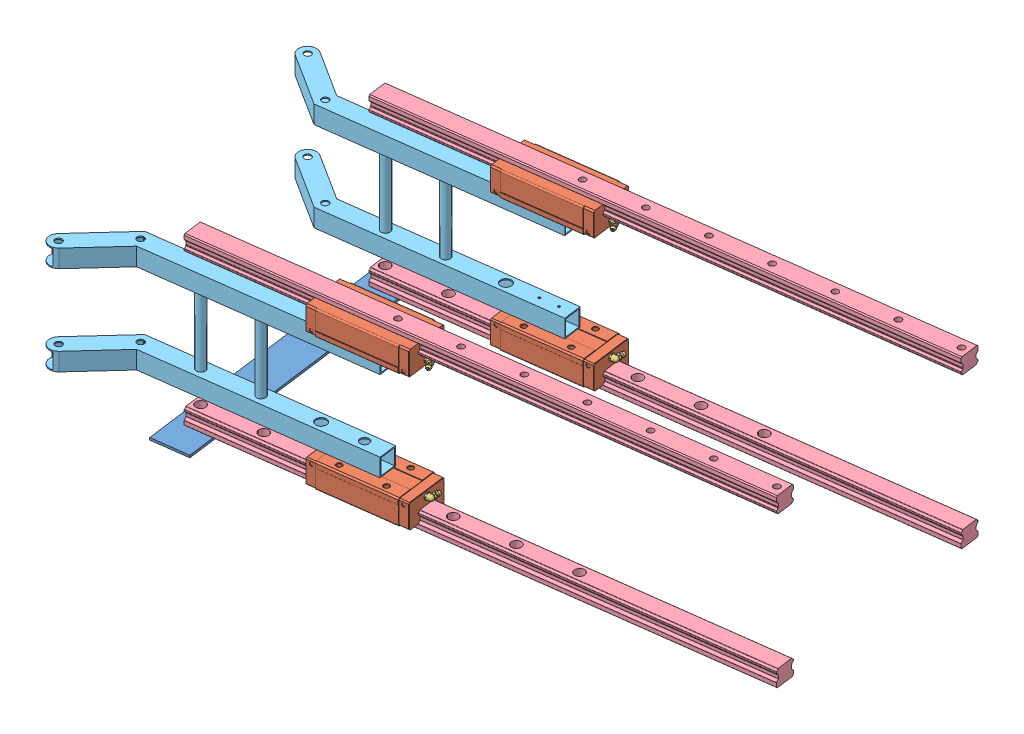
SolidWorks assembly armLayout, configuration Default. Lengths in mm.
Overall size (934.33 239.58 497.67).
19 component instances, 5 part files, 28 mates.
Components (placement in the parent):
- bottomSpacer-1: bottomSpacer [Default] at (-15.1295 99.3371 437.2342) x (-0.130526 0 -0.991445) z (0.991445 0 -0.130526) size (406.4 3.17 50.8)
- SHS30LV1SS Carriage-1: SHS30LV1SS Carriage [Default] at (446.9633 102.5121 222.6835) x (-0.991445 0 0.130526) z (-0.130526 0 -0.991445) size (142.6 35 60)
  - SHS30LVSSB-M6F1 Slide25-55-1: SHS30LVSSB-M6F1 Slide25-55 [Default] at (265.2705 7 0) size (131 35 60)
  - B-M6F-SHS_grease_nipple_joint-1: B-M6F-SHS_grease_nipple_joint [Default] at (199.7705 34 0) x (1 0 0) z (0 0.256332 0.966589) size (16.6 9.24 15.31)
- SHS30LV50010 Track-1: SHS30LV50010 Track [Default] at (728.5174 338.9121 493.0463) x (-0.991445 0 0.130526) z (0.130526 0 0.991445) size (750 23 28)
- SHS30LV1SS Carriage-2: SHS30LV1SS Carriage [Default] at (486.7476 338.9121 524.8759) x (-0.991445 0 0.130526) z (0.130526 0 0.991445) size (142.6 35 60)
  - SHS30LVSSB-M6F1 Slide25-55-1: SHS30LVSSB-M6F1 Slide25-55 [Default] at (265.2705 7 0) size (131 35 60)
  - B-M6F-SHS_grease_nipple_joint-1: B-M6F-SHS_grease_nipple_joint [Default] at (199.7705 34 0) x (1 0 0) z (0 0.256332 0.966589) size (16.6 9.24 15.31)
- SHS30LV1SS Carriage-3: SHS30LV1SS Carriage [Default] at (486.7476 102.5121 524.8759) x (-0.991445 0 0.130526) z (-0.130526 0 -0.991445) size (142.6 35 60)
  - SHS30LVSSB-M6F1 Slide25-55-1: SHS30LVSSB-M6F1 Slide25-55 [Default] at (265.2705 7 0) size (131 35 60)
  - B-M6F-SHS_grease_nipple_joint-1: B-M6F-SHS_grease_nipple_joint [Default] at (199.7705 34 0) x (1 0 0) z (0 0.256332 0.966589) size (16.6 9.24 15.31)
- SHS30LV1SS Carriage-4: SHS30LV1SS Carriage [Default] at (446.9633 338.9121 222.6835) x (-0.991445 0 0.130526) z (0.130526 0 0.991445) size (142.6 35 60)
  - SHS30LVSSB-M6F1 Slide25-55-1: SHS30LVSSB-M6F1 Slide25-55 [Default] at (265.2705 7 0) size (131 35 60)
  - B-M6F-SHS_grease_nipple_joint-1: B-M6F-SHS_grease_nipple_joint [Default] at (199.7705 34 0) x (1 0 0) z (0 0.256332 0.966589) size (16.6 9.24 15.31)
- SHS30LV50010 Track-2: SHS30LV50010 Track [Default] at (4.7627 102.5121 588.3304) x (0.991445 0 -0.130526) z (0.130526 0 0.991445) size (750 23 28)
- SHS30LV50010 Track-3: SHS30LV50010 Track [Default] at (-35.0217 102.5121 286.138) x (0.991445 0 -0.130526) z (0.130526 0 0.991445) size (750 23 28)
- SHS30LV50010 Track-4: SHS30LV50010 Track [Default] at (688.7331 338.9121 190.8539) x (-0.991445 0 0.130526) z (0.130526 0 0.991445) size (750 23 28)
- intakeArm-1: intakeArm [Default] at (-110.1995 296.9121 296.0354) x (-0.991445 0 0.130526) z (0.130526 0 0.991445) size (388.86 152.4 78.46)
- intakeArm-2: intakeArm [Default] at (-70.4151 144.5121 598.2278) x (-0.991445 0 0.130526) z (-0.130526 0 -0.991445) size (388.86 152.4 78.46)
Mates (geometry in assembly coordinates):
- Coincident11: coincident anti-aligned: plane of SHS30LV50010 Track-1 through (-6.6067 315.9121 578.5841) normal (0 -1 0); plane of SHS30LV1SS Carriage-2/SHS30LVSSB-M6F1 Slide25-55-1 through (157.352 315.9121 556.9985) normal (0 1 0)
- Coincident12: coincident: plane of SHS30LV50010 Track-1 through (-6.9791 320.5605 575.7554) normal (-0.130526 0 -0.991445); plane of SHS30LV1SS Carriage-2/SHS30LVSSB-M6F1 Slide25-55-1 through (156.9796 320.5605 554.1699) normal (0.130526 0 0.991445)
- Coincident13: coincident: plane of SHS30LV1SS Carriage-3/SHS30LVSSB-M6F1 Slide25-55-1 through (160.2619 125.5121 579.1017) normal (0 -1 0); plane of SHS30LV50010 Track-2 through (736.9769 125.5121 480.6894) normal (0 1 0)
- Coincident14: coincident: plane of SHS30LV1SS Carriage-3/SHS30LVSSB-M6F1 Slide25-55-1 through (160.6343 120.8637 581.9303) normal (-0.130526 0 -0.991445); plane of SHS30LV50010 Track-2 through (740.2593 122.6605 505.6213) normal (0.130526 0 0.991445)
- Coincident15: coincident: plane of SHS30LV50010 Track-1 through (740.2652 315.8616 505.6666) normal (0.991445 0 -0.130526); plane of SHS30LV50010 Track-2 through (740.2652 125.5626 505.6666) normal (0.991445 0 -0.130526)
- Coincident16: coincident anti-aligned: plane of SHS30LV1SS Carriage-1/SHS30LVSSB-M6F1 Slide25-55-1 through (120.4775 125.5121 276.9093) normal (0 -1 0); plane of SHS30LV50010 Track-3 through (697.1925 125.5121 178.497) normal (0 1 0)
- Coincident17: coincident: plane of SHS30LV1SS Carriage-1/SHS30LVSSB-M6F1 Slide25-55-1 through (117.1952 122.6605 251.9775) normal (0.130526 0 0.991445); plane of SHS30LV50010 Track-3 through (696.8201 120.8637 175.6684) normal (-0.130526 0 -0.991445)
- Coincident18: coincident: plane of SHS30LV1SS Carriage-4/SHS30LVSSB-M6F1 Slide25-55-1 through (117.5676 315.9121 254.8061) normal (0 1 0); plane of SHS30LV50010 Track-4 through (-46.3911 315.9121 276.3917) normal (0 -1 0)
- Coincident19: coincident: plane of SHS30LV1SS Carriage-4/SHS30LVSSB-M6F1 Slide25-55-1 through (117.1952 320.5605 251.9775) normal (0.130526 0 0.991445); plane of SHS30LV50010 Track-4 through (-46.7635 320.5605 273.5631) normal (-0.130526 0 -0.991445)
- Coincident20: coincident: plane of SHS30LV50010 Track-3 through (700.4808 125.5626 203.4742) normal (0.991445 0 -0.130526); plane of SHS30LV50010 Track-4 through (700.4808 315.8616 203.4742) normal (0.991445 0 -0.130526)
- Concentric16: concentric: circle of bottomSpacer-1; circle of SHS30LV50010 Track-3
- Coincident21: coincident: plane of bottomSpacer-1 through (-15.1295 102.5121 437.2342) normal (0 1 0); plane of SHS30LV50010 Track-3 through (700.2791 102.5121 201.9417) normal (0 -1 0)
- Concentric17: concentric: cylinder of bottomSpacer-1 through (4.7627 102.5121 588.3304) axis (0 -1 0) radius 6.35; circle of SHS30LV50010 Track-2
- Coincident22: coincident: plane of bottomSpacer-1 through (-15.1295 102.5121 437.2342) normal (0 1 0); plane of SHS30LV50010 Track-2 through (740.0635 102.5121 504.1341) normal (0 -1 0)
- Coincident31: coincident: plane of SHS30LV1SS Carriage-1/SHS30LVSSB-M6F1 Slide25-55-1 through (120.4775 125.5121 276.9093) normal (0 -1 0); plane of SHS30LV50010 Track-3 through (697.1925 125.5121 178.497) normal (0 1 0)
- Concentric18: concentric: cylinder of SHS30LV1SS Carriage-3/SHS30LVSSB-M6F1 Slide25-55-1 through (191.3927 132.9933 543.5875) axis (0 1 0) radius 3.3235; cylinder of intakeArm-2 through (31.8314 135.1076 564.5942) axis (0 1 0) radius 3.325
- Concentric19: concentric: circle of SHS30LV1SS Carriage-3/SHS30LVSSB-M6F1 Slide25-55-1; circle of intakeArm-2
- Coincident32: coincident anti-aligned: plane of SHS30LV1SS Carriage-3/SHS30LVSSB-M6F1 Slide25-55-1 through (175.3505 144.5121 594.1137) normal (0 1 0); plane of intakeArm-2 through (-70.4151 144.5121 598.2278) normal (0 -1 0)
- Concentric20: concentric: cylinder of SHS30LV1SS Carriage-2/SHS30LVSSB-M6F1 Slide25-55-1 through (256.1005 308.4309 575.4138) axis (0 -1 0) radius 3.3235; cylinder of SHS30LV1SS Carriage-3/SHS30LVSSB-M6F1 Slide25-55-1 through (256.1005 132.9933 575.4138) axis (0 1 0) radius 3.3235
- Coincident33: coincident anti-aligned: plane of SHS30LV1SS Carriage-2/SHS30LVSSB-M6F1 Slide25-55-1 through (173.001 296.9121 576.2677) normal (0 -1 0); plane of intakeArm-2 through (-70.4151 296.9121 598.2278) normal (0 1 0)
- Concentric21: concentric: cylinder of SHS30LV1SS Carriage-1/SHS30LVSSB-M6F1 Slide25-55-1 through (156.8294 132.9933 281.0529) axis (0 1 0) radius 3.3235; cylinder of SHS30LV1SS Carriage-4/SHS30LVSSB-M6F1 Slide25-55-1 through (156.8294 308.4309 281.0529) axis (0 -1 0) radius 3.3235
- Concentric22: concentric: cylinder of SHS30LV1SS Carriage-1/SHS30LVSSB-M6F1 Slide25-55-1 through (156.8294 132.9933 281.0529) axis (0 1 0) radius 3.3235; cylinder of intakeArm-1 through (-2.732 306.3166 302.0596) axis (0 -1 0) radius 3.325
- Concentric23: concentric: cylinder of SHS30LV1SS Carriage-1/SHS30LVSSB-M6F1 Slide25-55-1 through (211.095 132.9933 233.5636) axis (0 1 0) radius 3.3235; circle of intakeArm-1
- Coincident34: coincident anti-aligned: plane of SHS30LV1SS Carriage-1/SHS30LVSSB-M6F1 Slide25-55-1 through (130.6061 144.5121 254.2464) normal (0 1 0); plane of intakeArm-1 through (-110.1995 144.5121 296.0354) normal (0 -1 0)
- Coincident35: coincident anti-aligned: plane of SHS30LV1SS Carriage-4/SHS30LVSSB-M6F1 Slide25-55-1 through (128.2566 296.9121 236.4004) normal (0 -1 0); plane of intakeArm-1 through (-110.1995 296.9121 296.0354) normal (0 1 0)
- Parallel1: parallel: plane of bottomSpacer-1 through (-41.6524 102.5121 235.7726) normal (-0.130526 0 -0.991445); plane of SHS30LV50010 Track-3 through (696.8201 104.0121 175.6684) normal (-0.130526 0 -0.991445)
- Parallel2: parallel: plane of bottomSpacer-1 through (11.3934 102.5121 638.6958) normal (0.130526 0 0.991445); plane of SHS30LV50010 Track-2 through (740.2593 109.223 505.6213) normal (0.130526 0 0.991445)
- Linear/Linear Coupler1: linear coupler = 1 : 1 mm: plane of SHS30LV1SS Carriage-4/SHS30LVSSB-M6F1 Slide25-55-1 through (248.9018 331.9121 248.7588) normal (0.991445 0 -0.130526); plane of SHS30LV1SS Carriage-2/SHS30LVSSB-M6F1 Slide25-55-1 through (288.6862 331.9121 550.9512) normal (0.991445 0 -0.130526)
